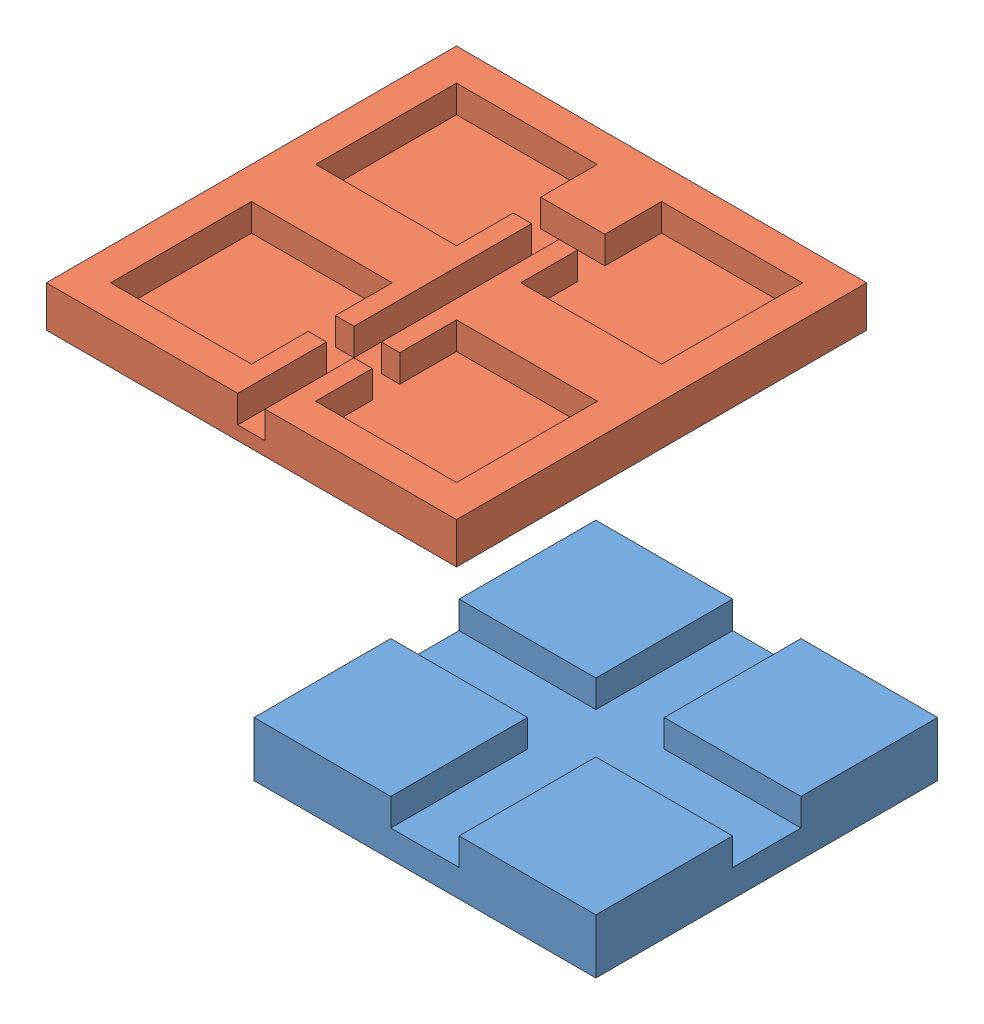
SolidWorks assembly button-assembly, configuration Default. Lengths in mm.
Overall size (61.26 4.13 51.06).
2 component instances, 2 part files, 0 mates.
Components (placement in the parent):
- top-1: top [Default] at origin size (25 4 25)
- bottom-2: bottom [Default] at (-33.7573 -0.1269 -23.5635) size (30 3 30)
